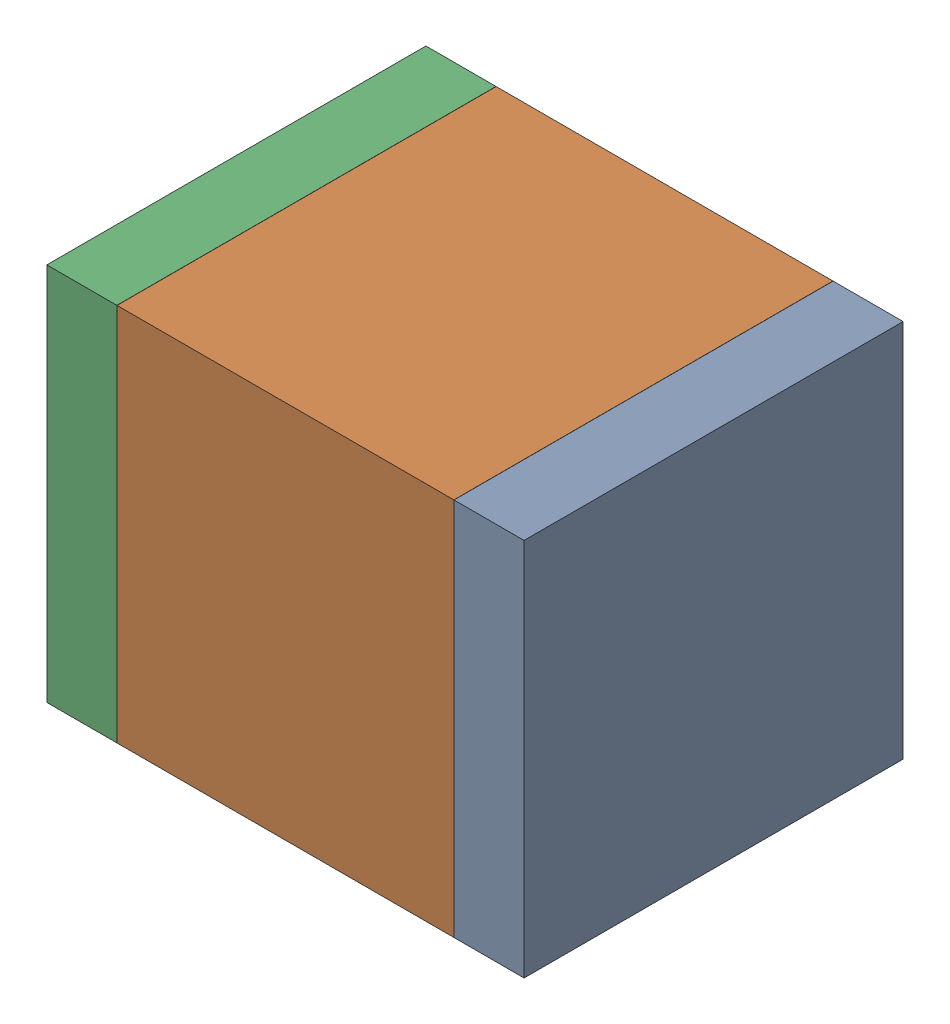
SolidWorks assembly C5, configuration Default. Lengths in mm.
Overall size (3.4 2.7 2.7).
6 component instances, 2 part files, 0 mates.
Components (placement in the parent):
- 6638393888-1: 6638393888 [Default] at (39.8688 19.3102 0) size (0.5 2.7 2.7)
  - Extruded_20-1: Extruded_20 [Default] at origin size (0.5 2.7 2.7)
- 6638393728-1: 6638393728 [Default] at (38.4188 19.3102 0) size (2.4 2.7 2.7)
  - Extruded_21-1: Extruded_21 [Default] at origin size (2.4 2.7 2.7)
- 6638393888-2: 6638393888 [Default] at (36.9688 19.3102 0) size (0.5 2.7 2.7)
  - Extruded_20-1: Extruded_20 [Default] at origin size (0.5 2.7 2.7)
